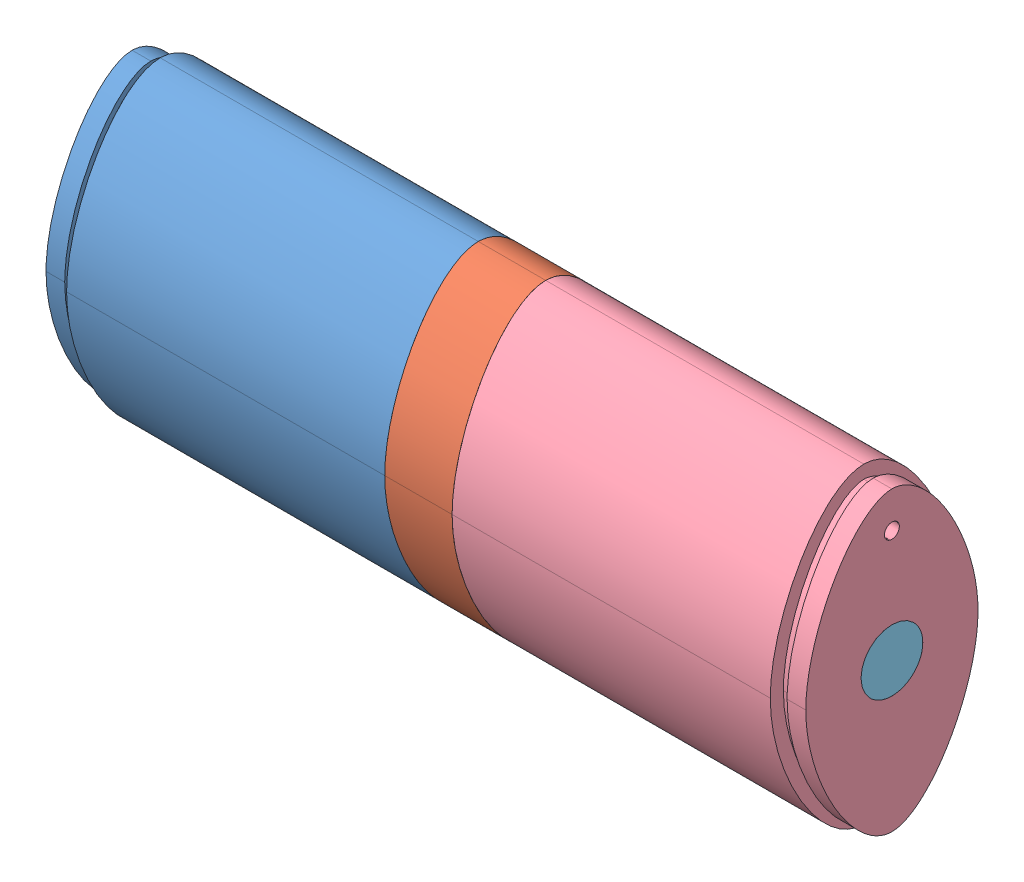
SolidWorks assembly 2mod_2cyl_1adap, configuration Default. Lengths in mm.
Overall size (406.02 166.67 100).
10 component instances, 10 part files, 18 mates.
Components (placement in the parent):
- segment0-1: segment0 [Default] at (-131.7557 1.2807 15.8869) size (200.02 166.67 100)
- couple0-1: couple0 [Default] at (-51.131 62.3803 -301.2272) size (36.02 166.67 100)
- pump0-1: pump0 [Default] at (-1.7557 1.2807 15.8869) x (0 -0.924225 -0.381849) z (1 0 0) size (33 33 70)
- segment1-1: segment1 [Default] at (74.2443 1.2807 15.8869) size (200.02 166.67 100)
- pump1-1: pump1 [Default] at (274.2443 1.2807 15.8869) x (0 0.924225 0.381849) z (-1 0 0) size (33 33 70)
- Part3^2mod_2cyl_1adap-1: Part3^2mod_2cyl_1adap [Default] at origin (virtual)
- chamber0_0-1: chamber0_0 [Default] at (-131.7557 1.2807 15.8869) size (155.01 156.21 42.52)
- chamber0_1-1: chamber0_1 [Default] at (-131.7557 1.2807 15.8869) size (155.01 156.21 42.52)
- chamber1_0-1: chamber1_0 [Default] at (74.2443 1.2807 15.8869) size (155.01 156.21 42.52)
- chamber1_1-1: chamber1_1 [Default] at (74.2443 1.2807 15.8869) size (155.01 156.21 42.52)
Mates (geometry in assembly coordinates):
- Coincident1: coincident aligned: plane of Module_and_inside-1 through (68.2443 -54.136 49.6369) normal (1 0 0); plane of Cylinder-1 through (68.2443 1.2807 15.8869) normal (1 0 0)
- Coincident2: coincident aligned: circle of Module_and_inside-1; circle of Cylinder-1
- Coincident3: coincident: point of Module_and_inside-1; point of Adapter-1
- Coincident4: coincident: point of Module_and_inside-1; point of Adapter-1
- Coincident5: coincident anti-aligned: plane of Module_and_inside-1 through (53.2443 1.2807 15.8869) normal (1 0 0); plane of Adapter-1 through (53.2443 56.6974 49.6369) normal (-1 0 0)
- Coincident6: coincident: point of Adapter-1; point of Module_and_inside-2
- Coincident7: coincident: point of Adapter-1; point of Module_and_inside-2
- Coincident8: coincident anti-aligned: plane of Adapter-1 through (89.2443 56.6974 49.6369) normal (1 0 0); plane of Module_and_inside-2 through (89.2443 1.2807 15.8869) normal (-1 0 0)
- Coincident9: coincident aligned: plane of Module_and_inside-2 through (274.2443 -54.136 49.6369) normal (1 0 0); plane of Cylinder-2 through (274.2443 1.2807 15.8869) normal (1 0 0)
- Coincident10: coincident anti-aligned: circle of Module_and_inside-2; circle of Cylinder-2
- Coincident11: coincident aligned: circle of Module_and_inside_assembly-1; circle of Module_and_inside-Intersect11-1
- Concentric1: concentric anti-aligned: cylinder of Module_and_inside_assembly-1 through (-143.0694 61.2807 15.8869) axis (1 0 0) radius 4; circle of Module_and_inside-Intersect11-1
- Coincident12: coincident aligned: circle of Module_and_inside_assembly-1; circle of Module_and_inside-Intersect1-1
- Concentric2: concentric anti-aligned: cylinder of Module_and_inside_assembly-1 through (-143.0694 61.2807 15.8869) axis (1 0 0) radius 4; circle of Module_and_inside-Intersect1-1
- Coincident13: coincident aligned: circle of Module_and_inside_assembly_2-1; circle of Module_and_inside-Intersect11-2
- Concentric3: concentric anti-aligned: circle of Module_and_inside_assembly_2-1; circle of Module_and_inside-Intersect11-2
- Coincident14: coincident aligned: circle of Module_and_inside_assembly_2-1; circle of Module_and_inside-Intersect1-2
- Concentric4: concentric anti-aligned: circle of Module_and_inside_assembly_2-1; circle of Module_and_inside-Intersect1-2
